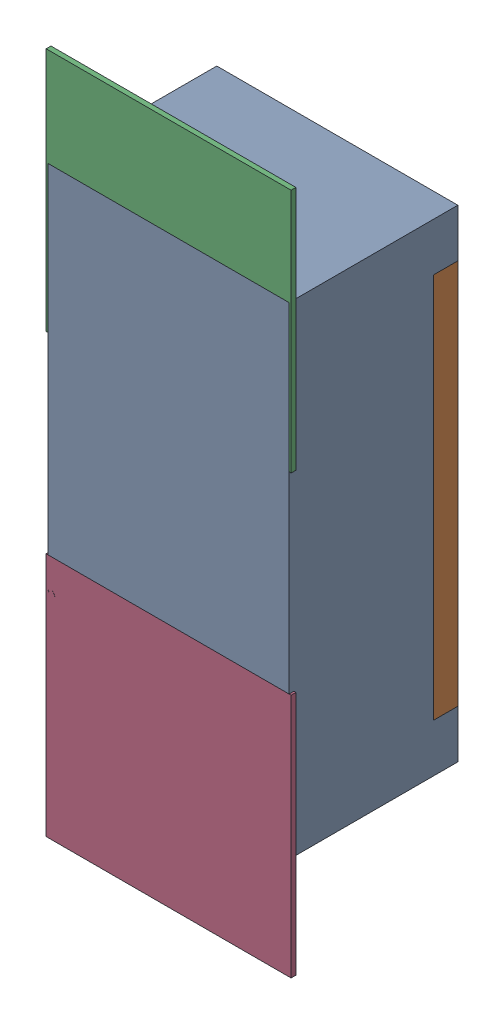
SolidWorks assembly R64, configuration Défaut. Lengths in mm.
Overall size (0.51 1.42 0.35).
5 component instances, 2 part files, 0 mates.
Components (placement in the parent):
- R0402-1: R0402 [Défaut] at (39.2683 -45.6168 -2.0818) x (0 1 0) z (0 0 -1) size (1 0.5 0.35)
- 6504207776-1: 6504207776 [Défaut] at (39.2684 -45.1668 -2.0918) size (0.51 0.51 0.01)
  - Extruded-1: Extruded [Défaut] at origin size (0.51 0.51 0.01)
- 6504207776-2: 6504207776 [Défaut] at (39.2684 -46.0739 -2.0918) size (0.51 0.51 0.01)
  - Extruded-1: Extruded [Défaut] at origin size (0.51 0.51 0.01)
